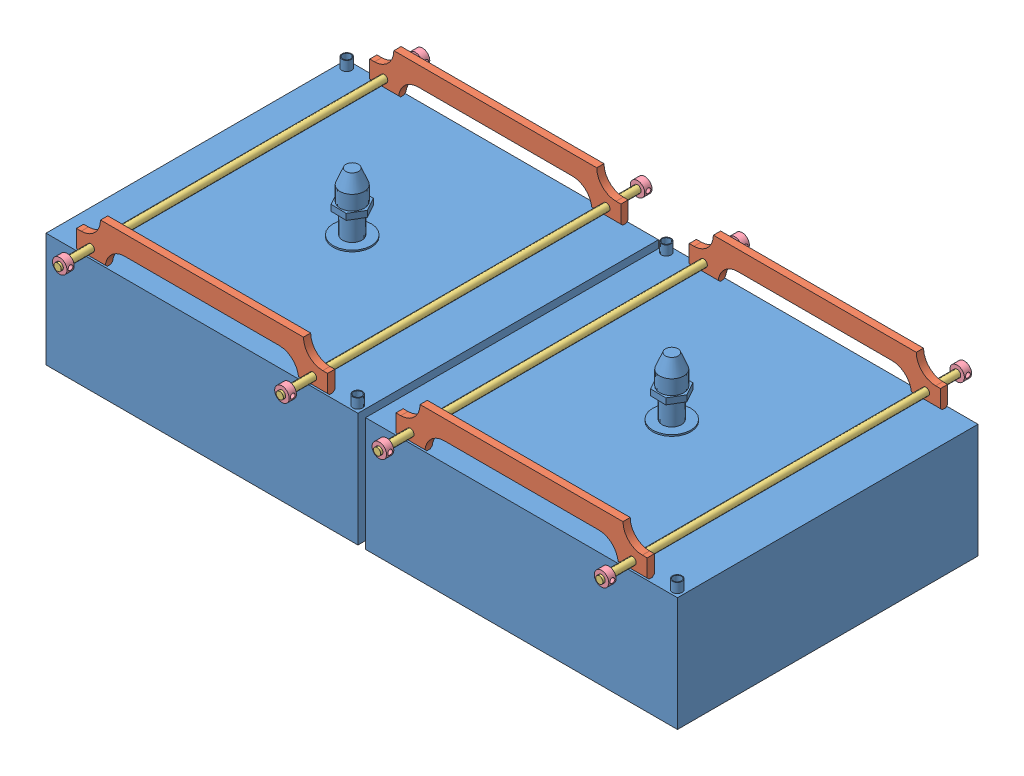
SolidWorks assembly 100-UltraSoundSource, configuration Default. Lengths in mm.
Overall size (830 228.1 482.6).
19 component instances, 4 part files, 18 mates.
Components (placement in the parent):
- 101-UltraSoundBox-1: 101-UltraSoundBox [Default] at (-210 0 0) size (410 228.1 395)
- 101-UltraSoundBox-2: 101-UltraSoundBox [Default] at (210 0 0) size (410 228.1 395)
- 102-RodHolder-1: 102-RodHolder [Default] at (-210 0 197.5) size (330.2 50.8 9.53)
- 102-RodHolder-4: 102-RodHolder [Default] at (210 0 197.5) size (330.2 50.8 9.53)
- 103-RodYokes-1: 103-RodYokes [Default] at origin size (9.53 9.52 482.6)
- 103-RodYokes-3: 103-RodYokes [Default] at (292.1 0 0) size (9.53 9.52 482.6)
- 103-RodYokes-4: 103-RodYokes [Default] at (712.1 0 0) size (9.53 9.52 482.6)
- 103-RodYokes-2: 103-RodYokes [Default] at (420 0 0) size (9.53 9.52 482.6)
- 102-RodHolder-2: 102-RodHolder [Default] at (-210 0 -188.0212) size (330.2 50.8 9.53)
- 102-RodHolder-3: 102-RodHolder [Default] at (210 0 -188.0212) size (330.2 50.8 9.53)
- 004-ShaftCollar_Mcmaster-9943K18-1: 004-ShaftCollar_Mcmaster-9943K18 [Default] at origin size (19.05 19.05 9.53) (hidden)
- 004-ShaftCollar_Mcmaster-9943K18-2: 004-ShaftCollar_Mcmaster-9943K18 [Default] at (0 0 233.68) size (19.05 19.05 9.53)
- 004-ShaftCollar_Mcmaster-9943K18-6: 004-ShaftCollar_Mcmaster-9943K18 [Default] at (0 0 -233.68) size (19.05 19.05 9.53)
- 004-ShaftCollar_Mcmaster-9943K18-7: 004-ShaftCollar_Mcmaster-9943K18 [Default] at (292.1 0 -233.68) size (19.05 19.05 9.53)
- 004-ShaftCollar_Mcmaster-9943K18-3: 004-ShaftCollar_Mcmaster-9943K18 [Default] at (292.1 0 233.68) size (19.05 19.05 9.53)
- 004-ShaftCollar_Mcmaster-9943K18-5: 004-ShaftCollar_Mcmaster-9943K18 [Default] at (420.0652 0 233.68) size (19.05 19.05 9.53)
- 004-ShaftCollar_Mcmaster-9943K18-9: 004-ShaftCollar_Mcmaster-9943K18 [Default] at (420.0652 0 -233.68) size (19.05 19.05 9.53)
- 004-ShaftCollar_Mcmaster-9943K18-4: 004-ShaftCollar_Mcmaster-9943K18 [Default] at (712.1652 0 233.68) size (19.05 19.05 9.53)
- 004-ShaftCollar_Mcmaster-9943K18-8: 004-ShaftCollar_Mcmaster-9943K18 [Default] at (712.1652 0 -233.68) size (19.05 19.05 9.53)
Mates (geometry in assembly coordinates):
- Coincident1: coincident aligned: plane of 101-UltraSoundBox-1 through (-210 0 0) normal (0 0 1); plane of assembly through (0 0 0) normal (0 0 1)
- Coincident2: coincident aligned: plane of 101-UltraSoundBox-1 through (-210 0 0) normal (0 1 0); plane of assembly through (0 0 0) normal (0 1 0)
- Distance1: distance = 5 mm aligned: plane of 101-UltraSoundBox-1 through (-5 150 197.5) normal (1 0 0); plane of assembly through (0 0 0) normal (1 0 0)
- InPlace1: in place: plane of 101-UltraSoundBox-1 through (-415 0 197.5) normal (0 0 1); plane of 102-RodHolder-1; moOrthogonalPlaneRef_w of 101-UltraSoundBox-1; plane of 102-RodHolder-1; moOrthogonalPlaneRef_w of 101-UltraSoundBox-1; plane of 102-RodHolder-1
- Coincident4: coincident aligned: plane of 101-UltraSoundBox-1; plane of 102-RodHolder-1
- Coincident5: coincident aligned: moOrthogonalPlaneRef_w of 101-UltraSoundBox-1 through (-210 0 197.5) axis (0 1 0); plane of 102-RodHolder-1 through (-210 0 197.5) normal (0 1 0)
- Coincident6: coincident anti-aligned: moOrthogonalPlaneRef_w of 101-UltraSoundBox-1 through (-210 0 197.5) axis (-1 0 0); plane of 102-RodHolder-1 through (-210 0 197.5) normal (1 0 0)
- InPlace2: in place: unknown of ?
- Coincident7: coincident aligned: plane of 103-RodYokes-1; plane of assembly
- Coincident8: coincident aligned: plane of ? through (0 0 0) normal (0 1 0)
- Coincident9: coincident anti-aligned: plane of ? through (0 0 0) normal (1 0 0)
- Concentric1: concentric anti-aligned: cylinder of 102-RodHolder-1 through (-63.95 162.7 187.975) axis (0 0 1) radius 4.7625; cylinder of 103-RodYokes-3 through (-63.95 162.7 241.3) axis (0 0 -1) radius 4.7625
- Coincident10: coincident aligned: plane of 103-RodYokes-1 through (-356.05 162.7 241.3) normal (0 0 1); plane of 103-RodYokes-3 through (-63.95 162.7 241.3) normal (0 0 1)
- Parallel1: parallel aligned: plane of 103-RodYokes-1 through (0 0 0) normal (0 1 0); plane of 103-RodYokes-3 through (292.1 0 0) normal (0 1 0)
- InPlace3: in place: unknown of ?
- Coincident11: coincident aligned: plane of 004-ShaftCollar_Mcmaster-9943K18-1; plane of assembly
- Coincident12: coincident aligned: plane of ? through (0 0 0) normal (0 1 0)
- Coincident13: coincident anti-aligned: plane of ? through (0 0 0) normal (1 0 0)
